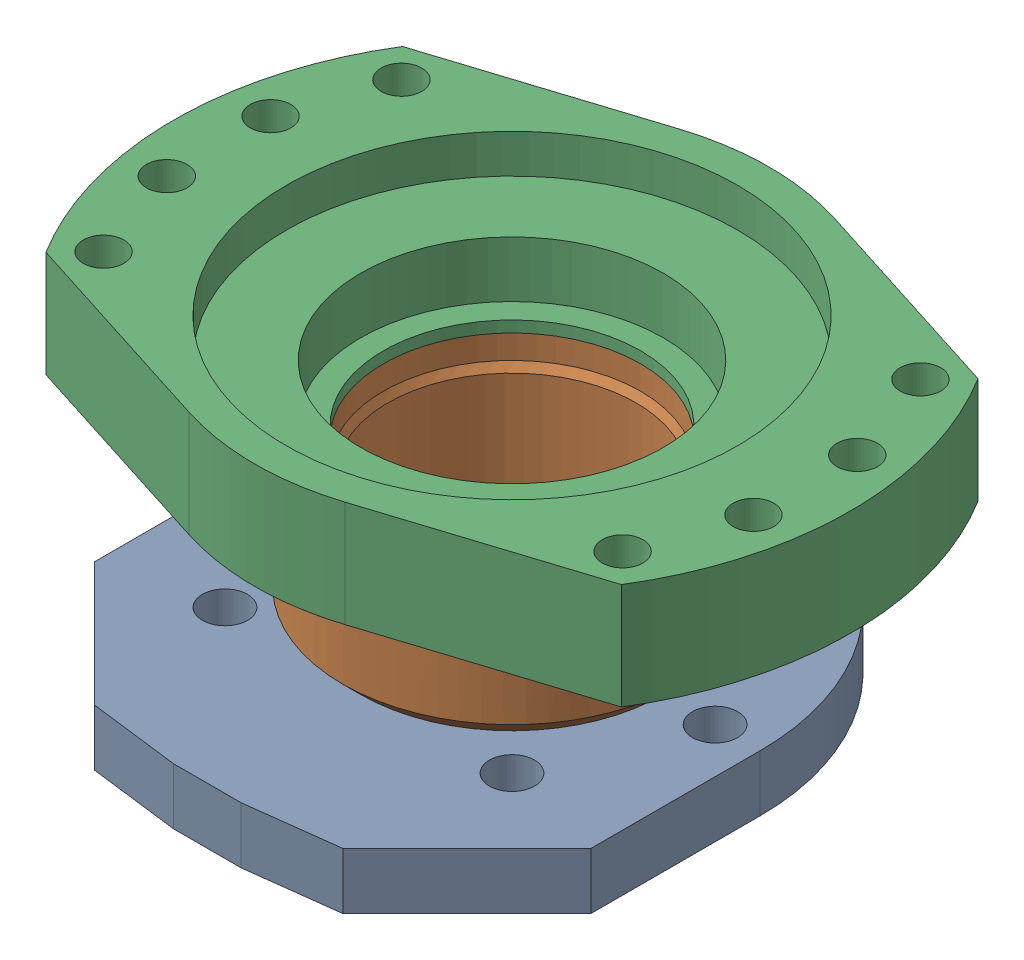
SolidWorks assembly g1_3_1_1_1_1_2, configuration 默认. Lengths in mm.
Overall size (300 154 249).
3 component instances, 3 part files, 0 mates.
Components (placement in the parent):
- g1_3_1_1_1_1-1_af0_2-1: g1_3_1_1_1_1-1_af0_2 [默认] at origin size (220 42 245)
- g1_3_1_1_1_1-2_af0_2-1: g1_3_1_1_1_1-2_af0_2 [默认] at (0 50 0) size (150 65.01 150)
- g1_3_1_1_1_1-3_af0_2-1: g1_3_1_1_1_1-3_af0_2 [默认] at (0 140 0) size (300 47 228)
